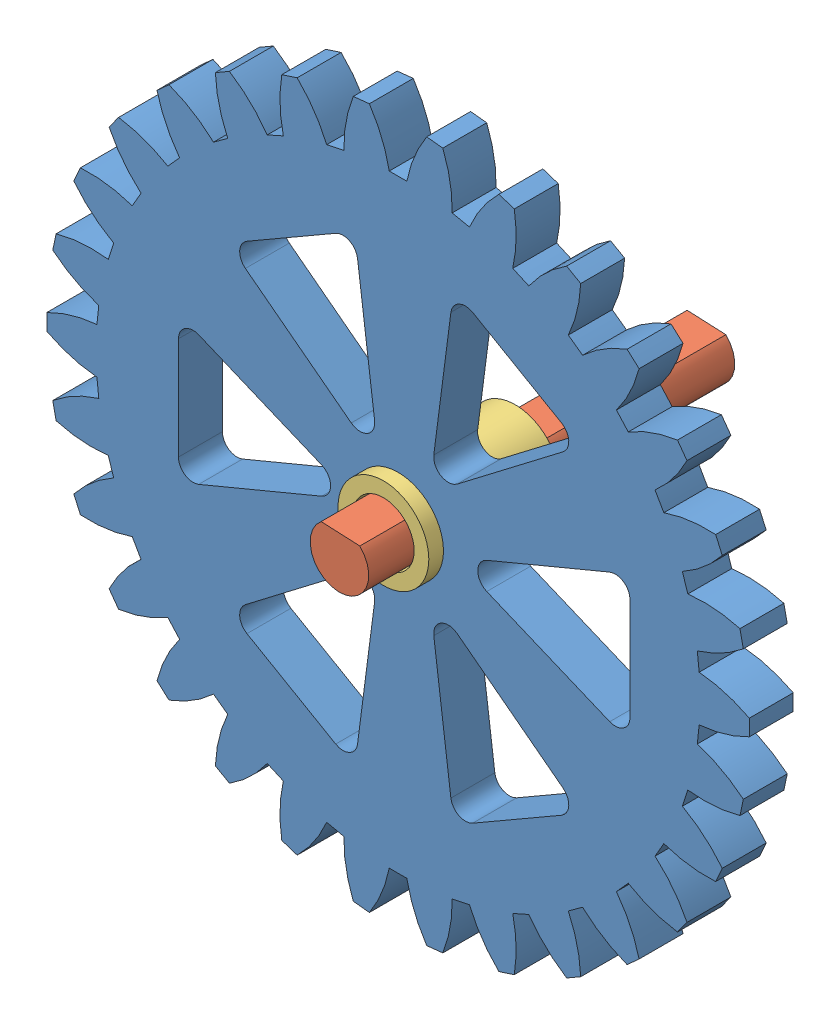
SolidWorks assembly Assem3, configuration Default. Lengths in mm.
Overall size (48 47.84 25).
4 component instances, 3 part files, 7 mates.
Components (placement in the parent):
- Root_gear-1: Root_gear [30T 1.5Mod] at (7.9367 27.6368 38.8525) size (48 47.84 3)
- axel-1: axel [25mm] at (7.9367 27.6368 20.8525) x (0.998946 -0.045893 0) z (0 0 1) size (4 3.5 25)
- spacer-1: spacer [1mm] at (7.9367 27.6368 41.8525) size (6.2 6.2 1)
- spacer-3: spacer [5mm ] at (7.9367 27.6368 33.8525) size (6.2 6.2 5)
Mates (geometry in assembly coordinates):
- Concentric4: concentric anti-aligned: cylinder of Root_gear-1 through (7.9367 27.6368 38.8525) axis (0 0 1) radius 2; cylinder of axel-1 through (7.9367 27.6368 45.8525) axis (0 0 -1) radius 2
- Parallel3: parallel aligned: line of Root_gear-1 through (9.327 29.0745 41.8525) axis (-0.998946 0.045893 0); line of axel-1 through (9.3291 29.0725 45.8525) axis (-0.998946 0.045893 0)
- Concentric5: concentric aligned: cylinder of axel-1 through (7.9367 27.6368 45.8525) axis (0 0 -1) radius 2; cylinder of spacer-1 through (7.9367 27.6368 42.8525) axis (0 0 -1) radius 2.1
- Coincident3: coincident anti-aligned: plane of Root_gear-1 through (7.9367 27.6368 41.8525) normal (0 0 1); plane of spacer-1 through (7.9367 27.6368 41.8525) normal (0 0 -1)
- Distance1: distance = 3 mm aligned: plane of axel-1 through (7.9367 27.6368 45.8525) normal (0 0 1); plane of spacer-1 through (7.9367 27.6368 42.8525) normal (0 0 1)
- Concentric6: concentric aligned: cylinder of axel-1 through (7.9367 27.6368 45.8525) axis (0 0 -1) radius 2; cylinder of spacer-3 through (7.9367 27.6368 38.8525) axis (0 0 -1) radius 2.1
- Coincident4: coincident anti-aligned: plane of Root_gear-1 through (7.9367 27.6368 38.8525) normal (0 0 -1); plane of spacer-3 through (7.9367 27.6368 38.8525) normal (0 0 1)
